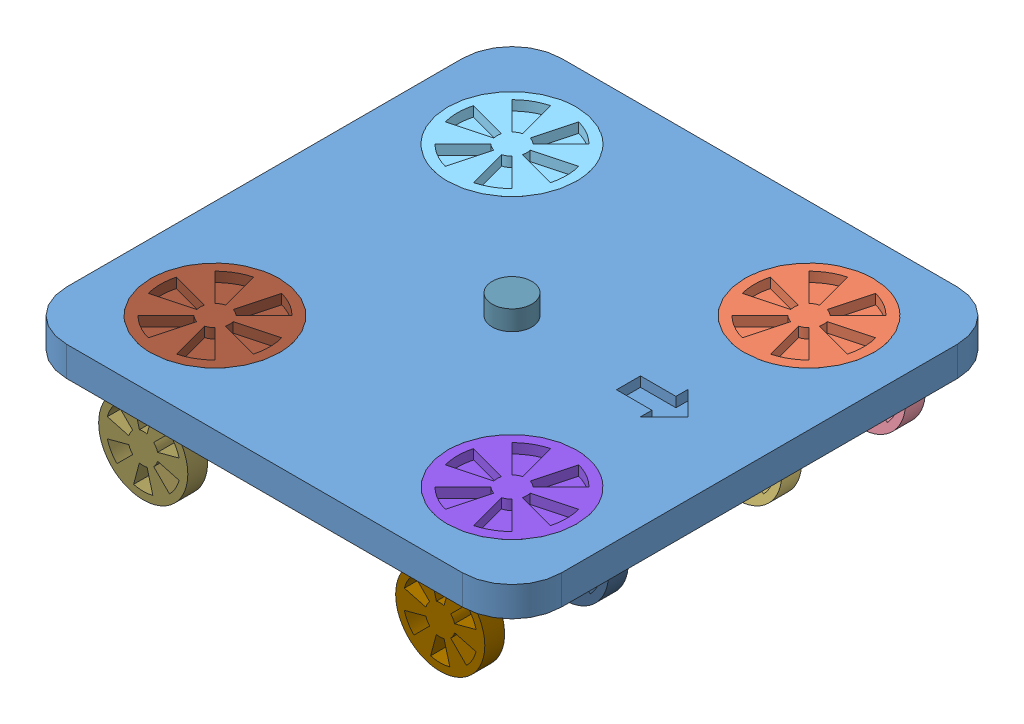
SolidWorks assembly robot_ehang, configuration 默认. Lengths in mm.
Overall size (500 145 500).
18 component instances, 14 part files, 10 mates.
Components (placement in the parent):
- base-1: base [默认] at origin size (500 30 500)
- turn_1-1: turn_1 [默认] at (148.6671 -19.4764 -280) size (130 125 145)
  - turntable_1-1: turntable_1 [默认] at (1.3329 19.4764 130) size (130 100 130)
  - wheel_1_1-1: wheel_1_1 [默认] at (1.3329 -30.5236 162.5) x (0 0 1) z (-1 0 0) size (40 90 90)
  - wheel_1_2-1: wheel_1_2 [默认] at (1.3329 -30.5236 97.5) x (0 0 -1) z (1 0 0) size (40 90 90)
- turn_2-1: turn_2 [默认] at (-149.3336 -14.5256 -280) size (130 125 145)
  - turntable_2-1: turntable_2 [默认] at (-0.6664 14.5256 130) size (130 100 130)
  - wheel_2_1-1: wheel_2_1 [默认] at (-0.6664 -35.4744 162.5) x (0 0 1) z (-1 0 0) size (40 90 90)
  - wheel_2_2-1: wheel_2_2 [默认] at (-0.6664 -35.4744 97.5) x (0 0 -1) z (1 0 0) size (40 90 90)
- turn_3-1: turn_3 [默认] at (144.1924 -17.6674 20) size (130 125 145)
  - turntable_3-1: turntable_3 [默认] at (5.8076 17.6674 130) size (130 100 130)
  - wheel_3_1-1: wheel_3_1 [默认] at (5.8076 -32.3326 162.5) x (0 0 1) z (-1 0 0) size (40 90 90)
  - wheel_3_2-1: wheel_3_2 [默认] at (5.8076 -32.3326 97.5) x (0 0 -1) z (1 0 0) size (40 90 90)
- turn_4-1: turn_4 [默认] at (-148.9527 -18.5243 20) size (130 125 145)
  - turntable_4-1: turntable_4 [默认] at (-1.0473 18.5243 130) size (130 100 130)
  - wheel_4_1-1: wheel_4_1 [默认] at (-1.0473 -31.4757 162.5) x (0 0 1) z (-1 0 0) size (40 90 90)
  - wheel_4_2-1: wheel_4_2 [默认] at (-1.0473 -31.4757 97.5) x (0 0 -1) z (1 0 0) size (40 90 90)
- body-1: body [默认] at origin size (40 50 40)
Mates (geometry in assembly coordinates):
- 同心1: concentric: cylinder of ? through (150 0 -150) axis (0 1 0) radius 65; cylinder of turn_1-1/turntable_1-1 through (150 30 -150) axis (0 -1 0) radius 65
- 重合1: coincident: plane of ? through (0 30 0) normal (0 1 0); plane of turn_1-1/turntable_1-1 through (150 30 -150) normal (0 1 0)
- 同心2: concentric: cylinder of ? through (-150 0 -150) axis (0 1 0) radius 65; cylinder of turn_2-1/turntable_2-1 through (-150 30 -150) axis (0 -1 0) radius 65
- 重合2: coincident: plane of ? through (0 30 0) normal (0 1 0); plane of turn_2-1/turntable_2-1 through (-150 30 -150) normal (0 1 0)
- 同心3: concentric: cylinder of ? through (150 0 150) axis (0 1 0) radius 65; cylinder of turn_3-1/turntable_3-1 through (150 30 150) axis (0 -1 0) radius 65
- 重合3: coincident: plane of ? through (0 30 0) normal (0 1 0); plane of turn_3-1/turntable_3-1 through (150 30 150) normal (0 1 0)
- 同心4: concentric: cylinder of ? through (-150 0 150) axis (0 1 0) radius 65; cylinder of turn_4-1/turntable_4-1 through (-150 30 150) axis (0 -1 0) radius 65
- 重合4: coincident: plane of ? through (0 30 0) normal (0 1 0); plane of turn_4-1/turntable_4-1 through (-150 30 150) normal (0 1 0)
- 同心5: concentric: cylinder of ? through (0 0 0) axis (0 1 0) radius 20; cylinder of ? through (0 50 0) axis (0 -1 0) radius 20
- 重合5: coincident: plane of ? through (0 0 0) normal (0 -1 0); plane of ? through (0 0 0) normal (0 -1 0)
